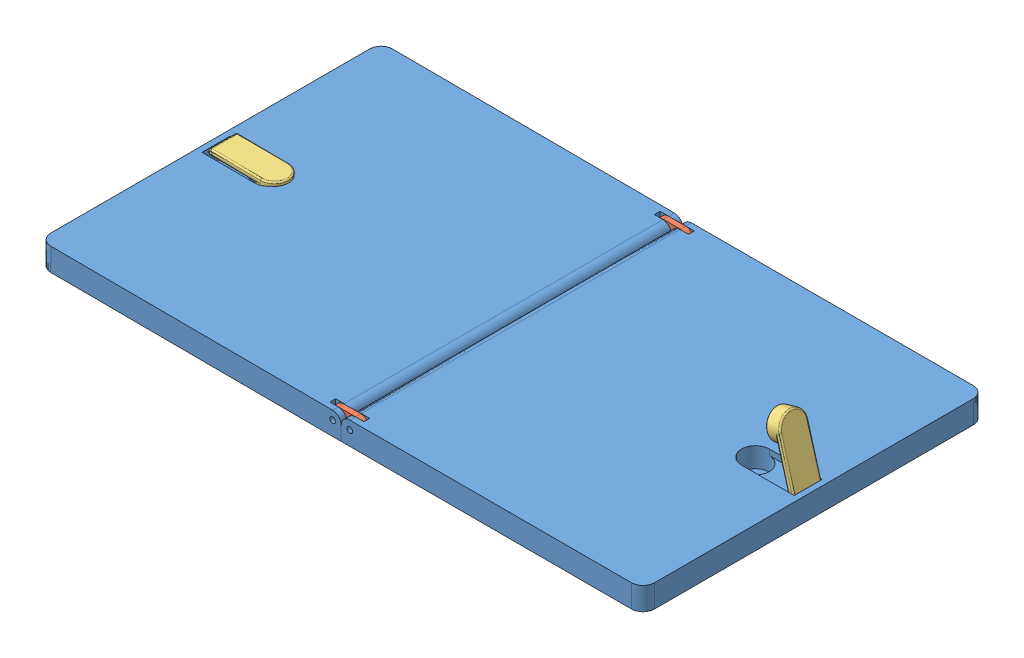
SolidWorks assembly 充电座(连杆)-装配体, configuration Default. Lengths in mm.
Overall size (212.02 28.84 120).
6 component instances, 3 part files, 4 mates.
Components (placement in the parent):
- 充电座(连杆)-右-1: 充电座(连杆)-右 [Default] at origin size (106 8 120)
- 充电座(连杆)-连杆-1: 充电座(连杆)-连杆 [Default] at (-109 -3.0116 56.1) x (0.999998 0.001941 0) z (0 0 1) size (12 6 1.9)
- 充电座(连杆)-连杆-2: 充电座(连杆)-连杆 [Default] at (-109 -3 -58) x (1 0 0) z (0 0 1) size (12 6 1.9)
- 充电座(连杆)-磁吸耳朵-1: 充电座(连杆)-磁吸耳朵 [Default] at (-11.6309 14.7403 0) x (0 0 1) z (-0.961921 -0.273326 0) size (9.8 23.4 5.2)
- 充电座(连杆)-右-2: 充电座(连杆)-右 [Default] at (-211.9871 0.4013 0) x (-0.999992 0.004009 0) z (0 0 -1) size (106 8 120)
- 充电座(连杆)-磁吸耳朵-2: 充电座(连杆)-磁吸耳朵 [Default] at (-190.4722 -3.378 -1.0217) x (0 0 -1) z (-0.009132 -0.999958 0) size (9.8 23.4 5.2)
Mates (geometry in assembly coordinates):
- 重合1: coincident anti-aligned: circle of 充电座(连杆)-右-1; circle of 充电座(连杆)-磁吸耳朵-1
- 重合2: coincident aligned: circle of 充电座(连杆)-右-1; circle of 充电座(连杆)-连杆-1
- 重合3: coincident aligned: circle of 充电座(连杆)-连杆-1; circle of 充电座(连杆)-右-2
- 相切3: tangent: circle of 充电座(连杆)-右-1; circle of 充电座(连杆)-右-2
